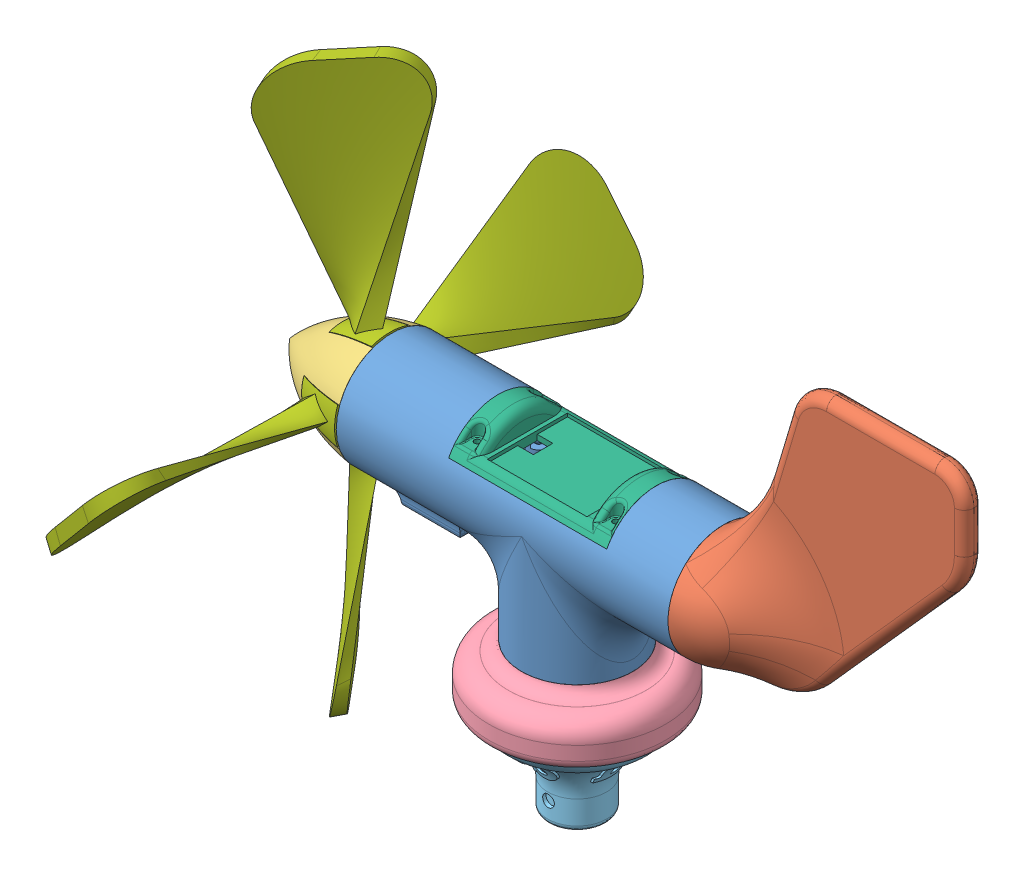
SolidWorks assembly Сборка2, configuration По умолчанию. Lengths in mm.
Overall size (350.62 283.14 283.64).
10 component instances, 7 part files, 12 mates.
Components (placement in the parent):
- основа-1: основа [По умолчанию] at origin size (170 88.5 57)
- хвост-1: хвост [По умолчанию] at (154.9289 -0.0285 0.0191) x (-1 0 0) z (0 0 -1) size (133.31 145.31 56.98)
- нос-1: нос [По умолчанию] x (-1 0 0) z (0 0 1) size (52.31 57 57)
- опора-1: опора [По умолчанию] at (95 -70 0) size (90.5 35 90.5)
- опора2-2: опора2 [По умолчанию] at (95 -90.2063 0) size (80 67 80)
- крышка-1: крышка [По умолчанию] at (135.5 0 0) x (0 0 1) z (-1 0 0) size (50.72 15.5 82.02)
- лопасть-2: лопасть [По умолчанию] x (-1 0 0) z (0 0 -1) size (48.15 141.57 57.04)
- лопасть-3: лопасть [По умолчанию] x (-1 0 0) z (0 -0.999842 0.017771) size (48.15 141.57 57.04)
- лопасть-4: лопасть [По умолчанию] x (-1 0 0) z (0 0 1) size (48.15 141.57 57.04)
- лопасть-5: лопасть [По умолчанию] x (-1 0 0) z (0 1 0) size (48.15 141.57 57.04)
Mates (geometry in assembly coordinates):
- Касательность5: tangent: circle of основа-1; circle of хвост-1
- Совпадение1: coincident: circle of основа-1; circle of нос-1
- Концентричный1: concentric: circle of основа-1; circle of опора-1
- Совпадение2: coincident: circle of основа-1; circle of опора-1
- Концентричный2: concentric: circle of опора-1; circle of опора2-2
- Параллельность2: parallel: line of основа-1 through (135.5 13 25.3624) axis (-1 0 0); line of крышка-1 through (54.5 13 25.3624) axis (1 0 0)
- Совпадение3: coincident: circle of основа-1; circle of крышка-1
- Совпадение17: coincident: circle of нос-1; circle of лопасть-2
- Совпадение19: coincident: plane of нос-1 through (-25 -9.7476 -26.7812) normal (0 0.939693 -0.34202); plane of лопасть-3 through (-25 -5.6433 -15.5049) normal (0 -0.939693 0.34202)
- Совпадение20: coincident: circle of нос-1; circle of лопасть-3
- Совпадение21: coincident: circle of нос-1; circle of лопасть-4
- Совпадение26: coincident: circle of нос-1; circle of лопасть-5
